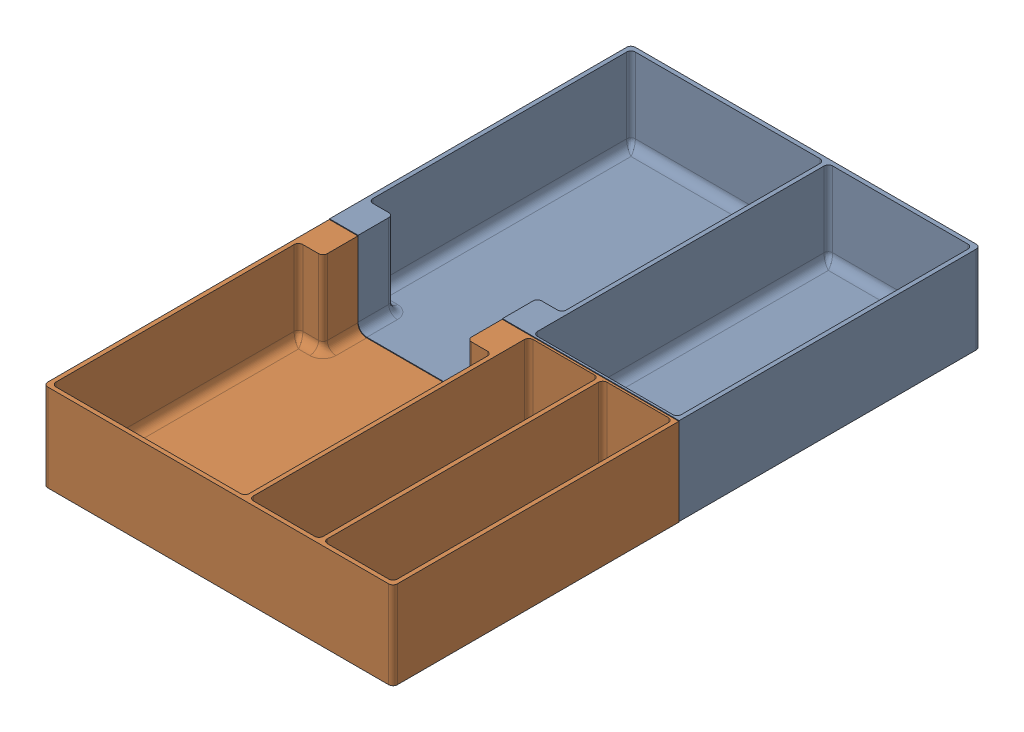
SolidWorks assembly KD Assem, configuration Default. Lengths in mm.
Overall size (254.01 63.83 426.89).
2 component instances, 2 part files, 0 mates.
Components (placement in the parent):
- Kitchen Drawer Holder_NEWMODEL-Split2-1: Kitchen Drawer Holder_NEWMODEL-Split2 [Default] at (-33.1487 -0.7808 89.3277) size (254 63.5 229.18)
- Kitchen Drawer Holder_NEWMODEL-Split1-1: Kitchen Drawer Holder_NEWMODEL-Split1 [Default] at (-33.1403 -1.1143 89.4943) size (254 63.5 207.7)
